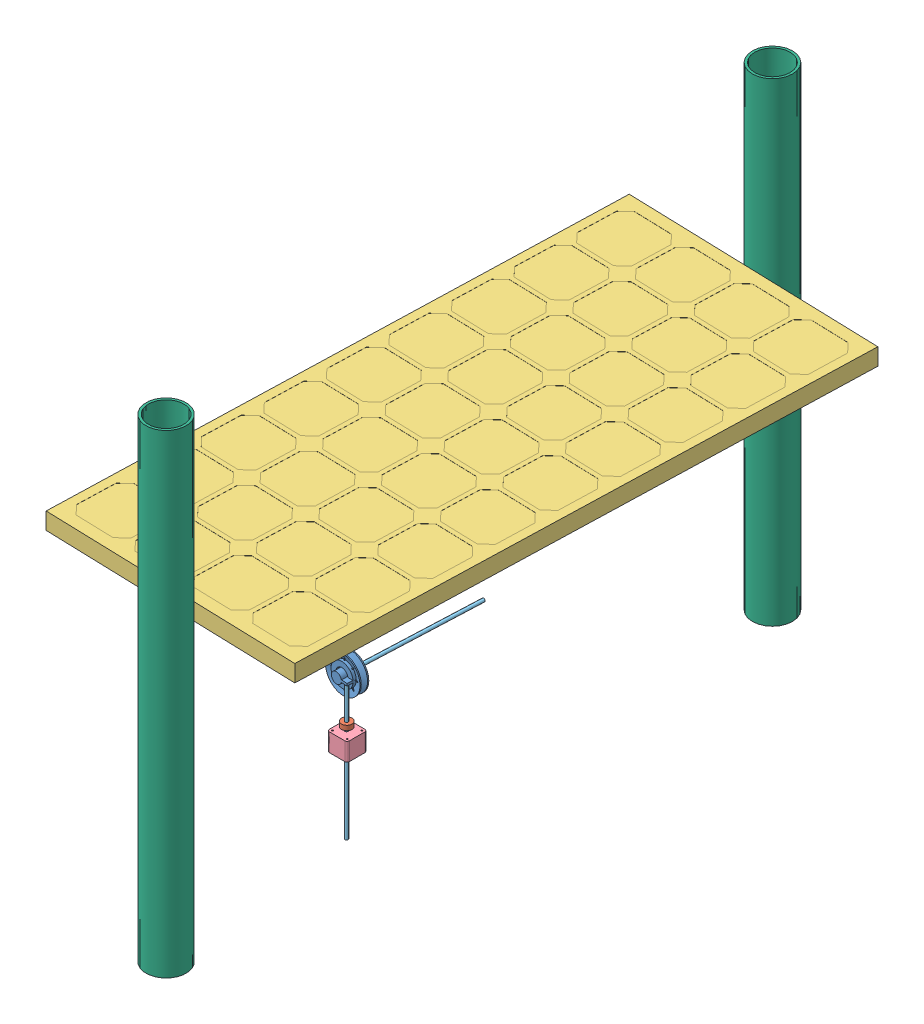
SolidWorks assembly Assem2, configuration Default. Lengths in mm.
Overall size (577.03 1002.37 1376.92).
8 component instances, 6 part files, 6 mates.
Components (placement in the parent):
- Drive Pulley-1: Drive Pulley [Default] at (71.5514 177.3587 -329.4417) x (-0.999048 0 -0.043619) z (0.043619 0 -0.999048) size (76.2 76.2 32.04)
- Nut-1: Nut [Default] at (89.5417 86.0553 -353.6008) x (0.698086 0 0.716014) z (-0.716014 0 0.698086) size (22 10 22)
- SOLAR PANEL ASSY-1: SOLAR PANEL ASSY [Default] at (69.5552 452.628 -616.5435) x (0.999539 0 0.030374) z (-0.030374 0 0.999539) size (541.02 35.56 1193.8)
- Stepper Base-1: Stepper Base [Default] at (96.2877 41.0411 -364.7822) size (42.3 38 42.3)
- Stepper Shaft-1: Stepper Shaft [Default] at (89.594 -118.7193 -353.1271) x (-0.154948 0 -0.987923) z (0.987923 0 -0.154948) size (6.8 282 6.8)
- Pipe-1: Pipe [Default] at (85.1845 -154.2475 -1255.5636) size (84.6 1000 84.6)
- Pipe-2: Pipe [Default] at (85.9716 -156.6144 23.8595) x (0.37972 0 -0.925101) z (0.925101 0 0.37972) size (84.6 1000 84.6)
- Stepper Shaft-2: Stepper Shaft [Default] at (85.3844 168.7575 -646.2697) x (0.998097 0.043619 0.043578) z (0.043578 -0.999048 0.001903) size (6.8 282 6.8)
Mates (geometry in assembly coordinates):
- Screw2: screw = 5 mm anti-aligned: cylinder of Stepper Base-1 through (89.594 79.0411 -353.1271) axis (0 1 0) radius 3.4; cylinder of Stepper Shaft-1 through (89.594 163.2807 -353.1271) axis (0 -1 0) radius 3.4
- Screw3: screw = 5 mm anti-aligned: cylinder of Nut-1 through (89.594 96.0553 -353.1271) axis (0 1 0) radius 3.4; cylinder of Stepper Shaft-1 through (89.594 163.2807 -353.1271) axis (0 -1 0) radius 3.4
- Tangent1: tangent anti-aligned: plane of SOLAR PANEL ASSY-1 through (-182.6996 488.188 -1221.3847) normal (0.030374 0 -0.999539); cylinder of Pipe-1 through (85.1845 845.7525 -1255.5636) axis (0 -1 0) radius 42.3
- Parallel2: parallel aligned: cylinder of Pipe-1 through (85.1845 845.7525 -1255.5636) axis (0 -1 0) radius 42.3; cylinder of Pipe-2 through (85.9716 843.3856 23.8595) axis (0 -1 0) radius 42.3
- Concentric5: concentric aligned: cylinder of Drive Pulley-1 through (73.7942 168.7575 -380.8096) axis (0.043619 0 -0.999048) radius 6.35; cylinder of Stepper Shaft-2 through (73.0838 168.7575 -364.5381) axis (0.043619 0 -0.999048) radius 3.4
- Coincident3: coincident anti-aligned: plane of Drive Pulley-1 through (73.0838 168.7575 -364.5381) normal (0.043619 0 -0.999048); plane of Stepper Shaft-2 through (73.0838 168.7575 -364.5381) normal (-0.043619 0 0.999048)
